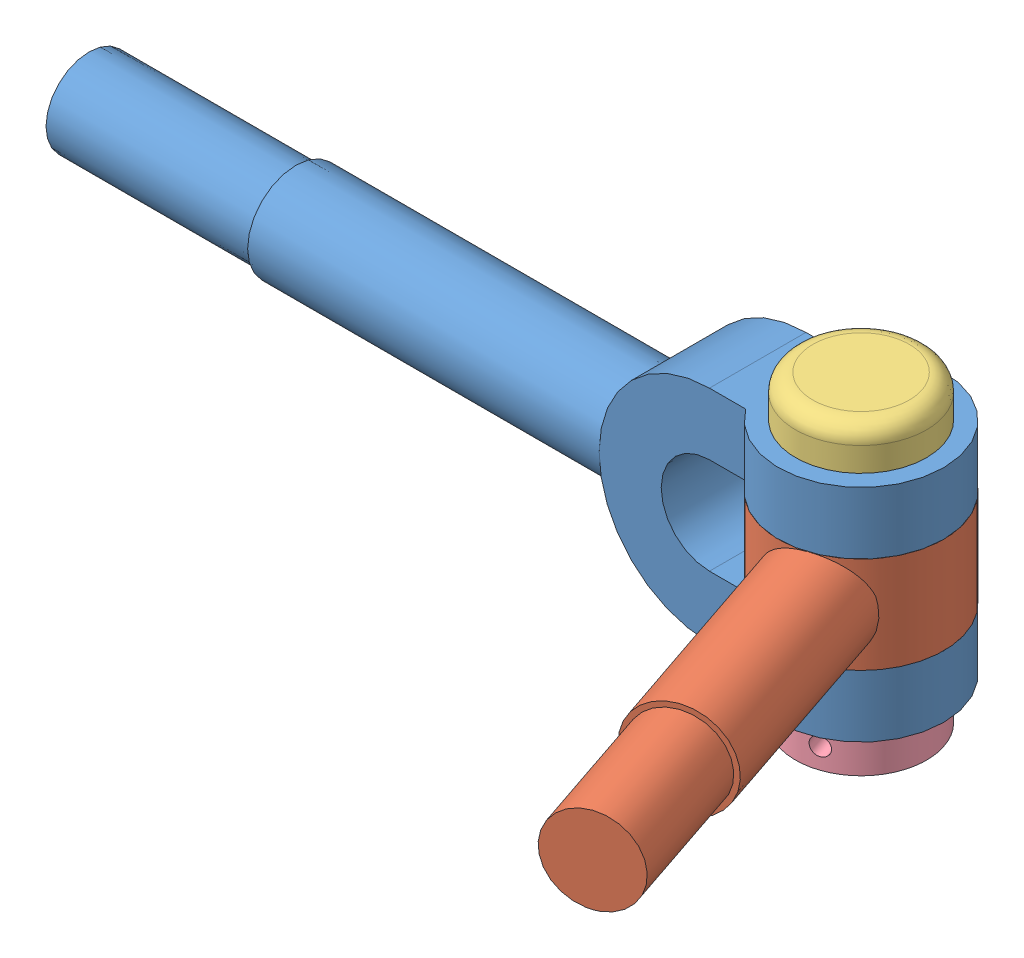
SolidWorks assembly knuckle joint, configuration Default. Lengths in mm.
Overall size (286.36 92 155.58).
4 component instances, 4 part files, 10 mates.
Components (placement in the parent):
- knuckle 1-2: knuckle 1 [Default] at origin size (248 64 48)
- Part2-2: Part2 [Default] x (0.319527 0 0.947577) z (0 1 0) size (148 48 28)
- knuckle part 3-4: knuckle part 3 [Default] at (0 -8 0) x (0.319527 0 0.947577) z (-0.947577 0 0.319527) size (38 92 38)
- knucle part 4-2: knucle part 4 [Default] at (0 -38 0) x (-0.319527 0 -0.947577) z (0 1 0) size (38 38 12)
Mates (geometry in assembly coordinates):
- Concentric5: concentric anti-aligned: circle of knuckle 1-2; circle of Part2-2
- Coincident2: coincident aligned: circle of knuckle 1-2; circle of Part2-2
- Concentric6: concentric aligned: cylinder of knuckle 1-2 through (0 -14 0) axis (0 -1 0) radius 24; cylinder of Part2-2 through (0 14 0) axis (0 -1 0) radius 24
- Coincident9: coincident anti-aligned: circle of knuckle 1-2; circle of knuckle part 3-4
- Concentric7: concentric aligned: circle of knuckle 1-2; circle of knuckle part 3-4
- Coincident20: coincident anti-aligned: plane of knuckle 1-2 through (-30 -32 14) normal (0 -1 0); plane of knucle part 4-2 through (0 -32 0) normal (0 1 0)
- Concentric11: concentric anti-aligned: circle of knuckle 1-2; circle of knucle part 4-2
- Parallel4: parallel anti-aligned: cylinder of knuckle part 3-4 through (-11.1834 -38 -33.1652) axis (0.319527 0 0.947577) radius 2.5; cylinder of knucle part 4-2 through (11.503 -38 34.1128) axis (-0.319527 0 -0.947577) radius 2.5749
- Coincident28: coincident anti-aligned: plane of Part2-2; plane of knucle part 4-2
- Lock4: lock: unknown of knuckle 1-2; unknown of knucle part 4-2
